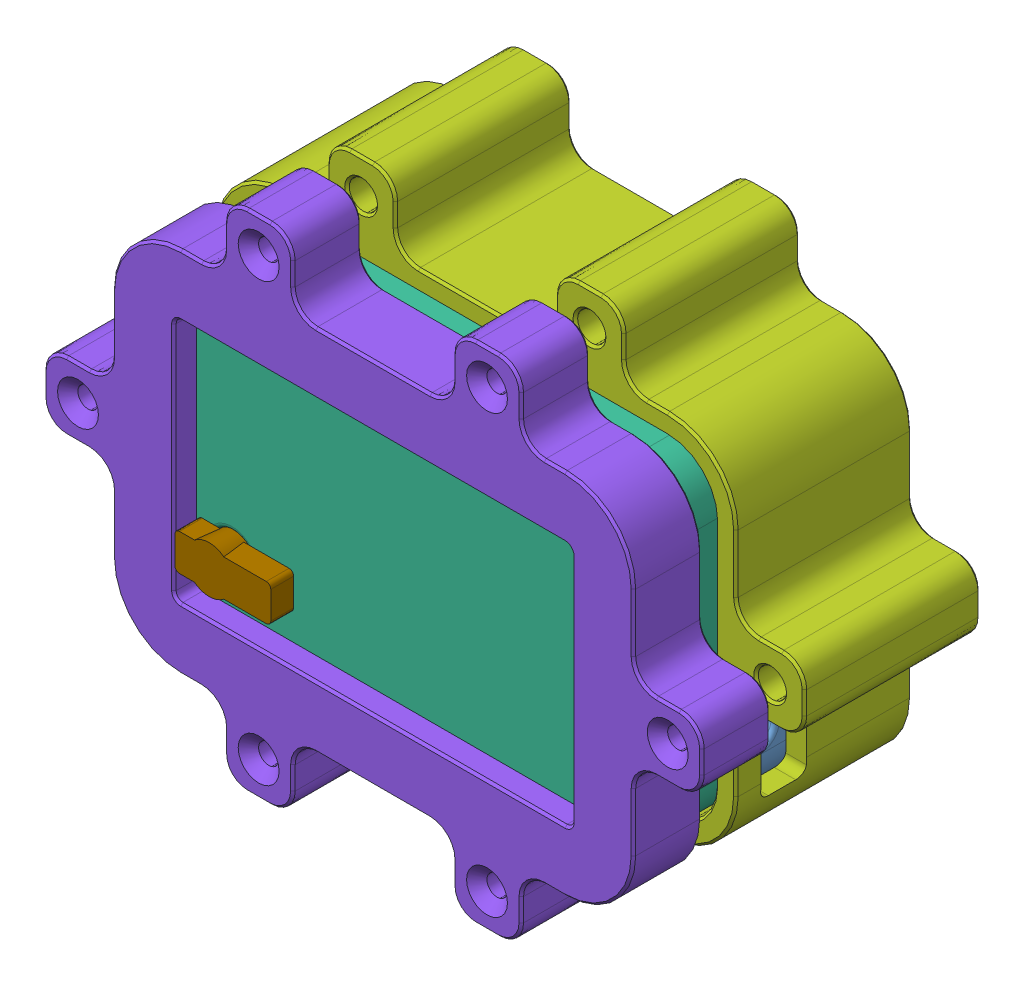
SolidWorks assembly ASSEM Potted Case Mold, configuration Default. Lengths in mm.
Overall size (144.13 110.58 60.94).
11 component instances, 11 part files, 22 mates.
Components (placement in the parent):
- Mold v3 Female-1: Mold v3 Female [Default] at (191.5997 87.9143 43.5047) size (104 70.5 24.7)
- (B)ear Tag_7_30_2020-1: (B)ear Tag_7_30_2020 [with ribbons] at (37.6699 26.3551 51.0047) x (1 0 0) z (0 -1 0) size (93.35 45.93 46.24)
- ww02_Board_Render-1: ww02_Board_Render [Main] at (100.5199 61.407 50.8547) x (-1 0 0) z (0 1 0) size (71.57 32.02 37.03)
- screw-1: screw [Default] at (37.6699 36.8551 66.8797) x (0.98042 0 0.196919) z (-0.196919 0 0.98042) size (7.92 20.76 7.66)
- 90592A090_STEEL HEX NUT-1: 90592A090_STEEL HEX NUT [90592A090] at (37.6699 41.2551 66.8797) size (7 3.75 8.08)
- Mold v3 Male-1: Mold v3 Male [Default] at (191.5997 87.9143 43.5047) size (104 70.5 35.56)
- Mold Clamp 2-1: Mold Clamp 2 [Default] at (192.0997 88.4143 26.048) x (1 0 0) z (0 -1 0) size (144.13 38.5 110.58)
- Mold Clamp 1-1: Mold Clamp 1 [Default] at (39.1437 26.3551 58.4447) x (1 0 0) z (0 -1 0) size (144.13 26.4 110.58)
- urethane reservoir-1: urethane reservoir [Default] at origin (suppressed, hidden)
- Plug RevB-1: Plug RevB [Default] at (2.332 42.138 82.4447) x (-1 0 0) z (0 1 0) size (21 15.97 10.39)
- wire plug-1: wire plug [Default] at (37.6699 18.8515 66.8797) x (0.999998 0 -0.001791) z (0.001791 0 0.999998) size (6 17.8 6)
Mates (geometry in assembly coordinates):
- Coincident1: coincident aligned: plane of Mold v3 Male v2-1 through (-13.764 84.138 109.5447) normal (-1 0 0); plane of Mold v3 Female-1 through (-13.764 84.138 109.5447) normal (-1 0 0)
- Coincident2: coincident aligned: plane of Mold v3 Male v2-1 through (79.736 94.638 109.5447) normal (0 1 0); plane of Mold v3 Female-1 through (79.736 94.638 109.5447) normal (0 1 0)
- Coincident3: coincident anti-aligned: plane of Mold v3 Male v2-1 through (90.246 42.8551 66.8797) normal (0 0 -1); plane of Mold v3 Female-1 through (90.246 42.8551 66.8797) normal (0 0 1)
- Coincident4: coincident anti-aligned: plane of Mold v3 Female-1 through (79.736 34.638 43.5047) normal (0 0 -1); plane of Mold Clamp v3 2-1 through (80.236 84.638 43.5047) normal (0 0 1)
- Distance1: distance = 0.5 mm anti-aligned: plane of Mold v3 Female-1 through (90.236 34.638 109.5447) normal (1 0 0); plane of Mold Clamp v3 2-1 through (90.736 84.638 219.2114) normal (-1 0 0)
- Distance2: distance = 0.5 mm anti-aligned: plane of Mold v3 Male v2-1 through (79.736 94.638 109.5447) normal (0 1 0); plane of Mold Clamp v3 2-1 through (-3.8901 95.138 219.2114) normal (0 -1 0)
- Coincident5: coincident anti-aligned: plane of Mold v3 Male v2-1 through (191.5997 87.9143 94.4447) normal (0 0 1); plane of Mold Clamp 1-1 through (-3.8901 34.0575 94.4447) normal (0 0 -1)
- Distance3: distance = 0.5 mm anti-aligned: plane of Mold v3 Male v2-1 through (90.236 34.638 109.5447) normal (1 0 0); plane of Mold Clamp 1-1 through (90.736 34.0575 84.4447) normal (-1 0 0)
- Distance5: distance = 0.5 mm anti-aligned: plane of Mold Clamp 1-1 through (80.236 95.138 84.4447) normal (0 -1 0); plane of Mold v3 Male v2-1 through (79.736 94.638 109.5447) normal (0 1 0)
- Coincident8: coincident anti-aligned: plane of (B)ear Tag_7_30_2020-1 through (66.6699 61.3551 50.8047) normal (0 0 1); plane of ww02_Board_Render-1 through (16.5099 59.8551 50.8047) normal (0 0 -1)
- Coincident9: coincident anti-aligned: plane of (B)ear Tag_7_30_2020-1 through (7.4699 61.3551 80.0047) normal (1 0 0); plane of ww02_Board_Render-1 through (7.4699 59.8551 53.6547) normal (-1 0 0)
- Coincident10: coincident anti-aligned: plane of (B)ear Tag_7_30_2020-1 through (8.6699 59.8551 52.0047) normal (0 1 0); plane of ww02_Board_Render-1 through (7.4699 59.8551 53.6547) normal (0 -1 0)
- Concentric3: concentric aligned: cylinder of Mold v3 Female-1 through (37.6699 67.4551 74.5047) axis (1 0 0) radius 12.25; cylinder of (B)ear Tag_7_30_2020-1 through (37.6699 67.4551 74.5047) axis (1 0 0) radius 12.25
- Concentric4: concentric aligned: cylinder of Mold v3 Female-1 through (37.6699 500026.3551 66.8797) axis (0 -1 0) radius 2; cylinder of (B)ear Tag_7_30_2020-1 through (37.6699 500026.3551 66.8797) axis (0 -1 0) radius 2
- Coincident11: coincident aligned: plane of screw-1 through (38.6503 42.8551 67.0766) normal (0 1 0); plane of 90592A090_STEEL HEX NUT-1 through (34.1699 42.8551 64.8589) normal (0 1 0)
- Concentric5: concentric aligned: cylinder of screw-1 through (37.6699 46.0284 66.8797) axis (0 1 0) radius 1; circle of 90592A090_STEEL HEX NUT-1
- Concentric6: concentric anti-aligned: cylinder of (B)ear Tag_7_30_2020-1 through (37.6699 500026.3551 66.8797) axis (0 -1 0) radius 2; cylinder of screw-1 through (37.6699 46.0284 66.8797) axis (0 1 0) radius 1
- Coincident13: coincident anti-aligned: plane of (B)ear Tag_7_30_2020-1 through (37.6699 57.3551 66.8797) normal (0 -1 0); plane of screw-1 through (37.6699 57.3551 66.8797) normal (0 1 0)
- Coincident15: coincident anti-aligned: plane of Plug RevB-1 through (2.332 42.138 94.4447) normal (0 0 -1); plane of Mold v3 Male v2-1 through (191.5997 87.9143 94.4447) normal (0 0 1)
- Concentric8: concentric aligned: cone of Mold v3 Male v2-1 through (2.332 42.138 83.0062) axis (0 0 -1); cone of Plug RevB-1 through (2.332 42.138 82.4447) axis (0 0 -1)
- Concentric9: concentric aligned: cylinder of Mold v3 Female-1 through (37.6699 57.9112 66.8797) axis (0 -1 0) radius 4.05; cylinder of wire plug-1 through (37.6699 36.6515 66.8797) axis (0 -1 0) radius 3
- Parallel1: parallel anti-aligned: plane of Plug RevB-1 through (2.332 42.138 82.4447) normal (-1 0 0)
